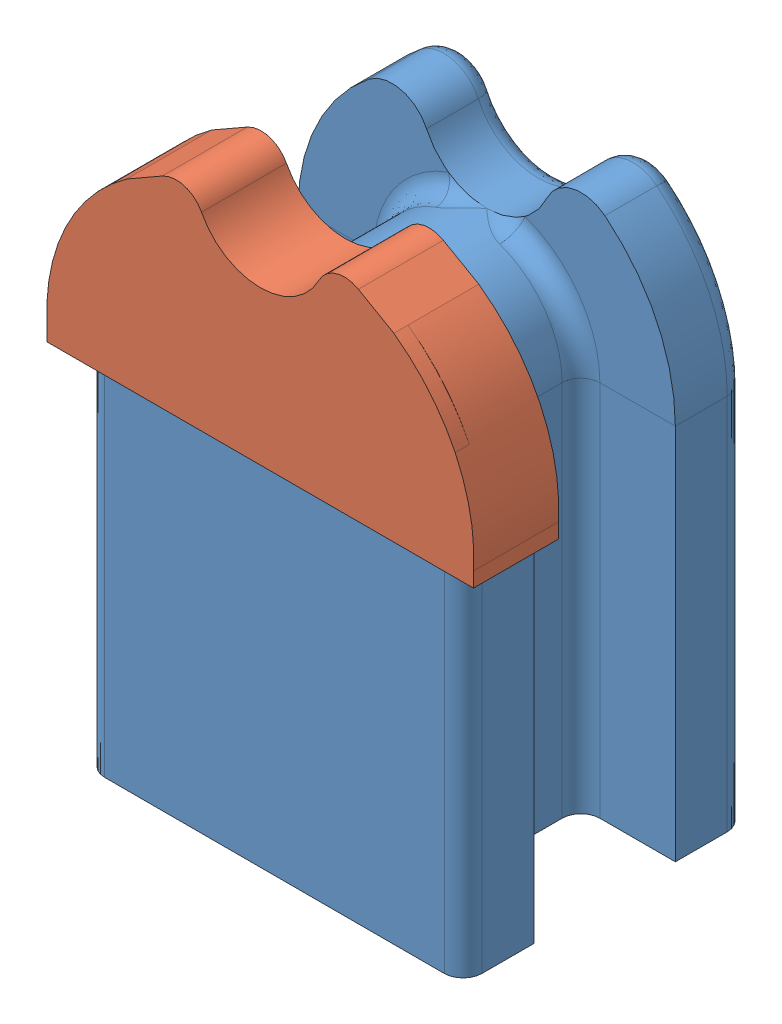
SolidWorks assembly raiser assembly 2, configuration Default. Lengths in mm.
Overall size (22.64 30.08 15.75).
2 component instances, 2 part files, 1 mates.
Components (placement in the parent):
- tube support-1: tube support [Default] at (10.9911 -1.94 23.1719) size (20 28.24 15)
- add on 4-1: add on 4 [Default] at (-6.7868 12.9603 29.7569) size (22.64 10.87 4.5)
Mates (geometry in assembly coordinates):
- Coincident1: coincident: plane of tube support-1 through (20.9911 -6.94 26.9219) normal (0 0 -1); plane of add on 4-1 through (20.9911 18.06 26.9219) normal (0 0 -1)
